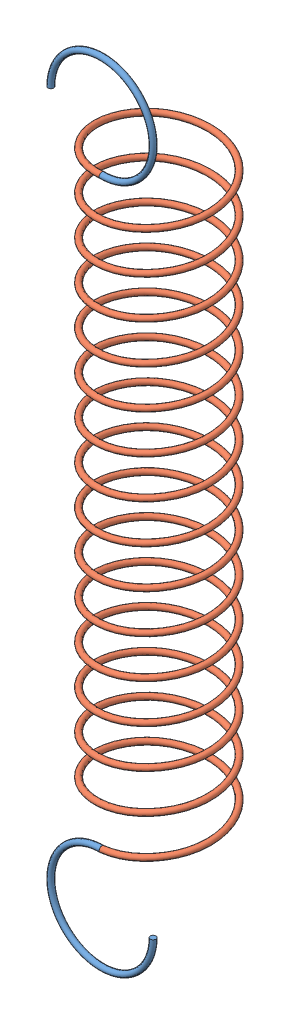
SolidWorks assembly Mola de Tração, configuration Valor predeterminado. Lengths in mm.
Overall size (12.12 69.87 10.5).
3 component instances, 2 part files, 8 mates.
Components (placement in the parent):
- BDT_G_F_10_v01-1: BDT_G_F_10_v01 [Valor predeterminado] at (0 52.8408 0) size (9.5 9.5 0.5)
- BDT_G_F_10_v01-2: BDT_G_F_10_v01 [Valor predeterminado] at (0 -7.5268 0) x (0 -1 0) z (0 0 -1) size (9.5 9.5 0.5)
- BDT_G_F_09_v01-1: BDT_G_F_09_v01 [Valor predeterminado] at (0.0033 -16.4004 -5) x (0 0 1) z (-1 0 0) size (10.5 52.37 12.12)
Mates (geometry in assembly coordinates):
- Coincidente17: coincident anti-aligned: plane of BDT_G_F_10_v01-1 through (0 48.3408 0) normal (-1 0 0); plane of BDT_G_F_10_v01-2 through (0 -3.0268 0) normal (1 0 0)
- Paralelo2: parallel anti-aligned: plane of BDT_G_F_10_v01-1 through (-4.5 52.8408 0) normal (0 -1 0); plane of BDT_G_F_10_v01-2 through (4.5 -7.5268 0) normal (0 1 0)
- Coincidente23: coincident anti-aligned: circle of BDT_G_F_10_v01-1; circle of ?
- Coincidente25: coincident anti-aligned: plane of BDT_G_F_10_v01-1 through (0 52.8408 0) normal (0 0 1); plane of BDT_G_F_10_v01-2 through (0 -7.5268 0) normal (0 0 -1)
- DistânciaLimite1: limit distance = 60.3675 mm anti-aligned: plane of BDT_G_F_10_v01-1 through (0 52.8408 0) normal (0 1 0); plane of BDT_G_F_10_v01-2 through (0 -7.5268 0) normal (0 -1 0)
- Coincidente27: coincident aligned: plane of BDT_G_F_10_v01-1 through (0 52.8408 0) normal (1 0 0); plane of assembly through (0 0 0) normal (1 0 0)
- Distância2: distance = 5 mm aligned: plane of BDT_G_F_09_v01-1 through (0.0033 -16.4004 -5) normal (0 0 1); plane of assembly through (0 0 0) normal (0 0 1)
- Coincidente29: coincident anti-aligned: plane of BDT_G_F_10_v01-2 through (0 -7.5268 0) normal (0 0 -1); plane of assembly through (0 0 0) normal (0 0 1)
